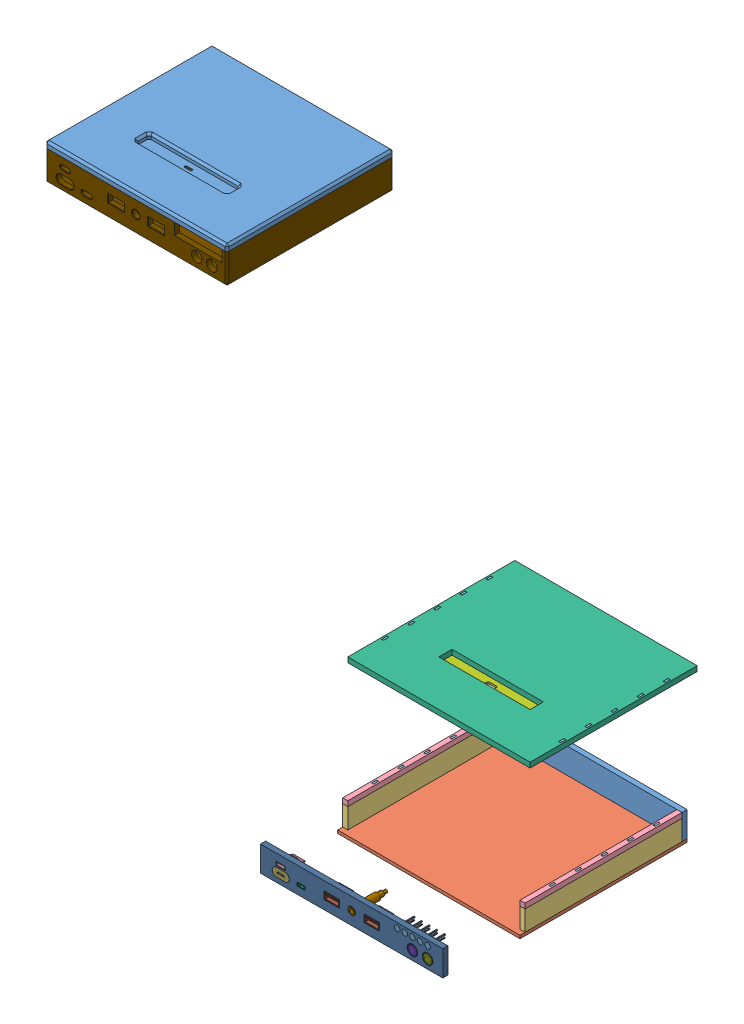
SolidWorks assembly Assem1, configuration Default. Lengths in mm.
Overall size (868.83 145.86 641.02).
69 component instances, 24 part files, 150 mates.
Components (placement in the parent):
- Back rail-1: Back rail [Default] at (72.2044 136.4605 98.1346) size (180 25 5)
- Bottom-1: Bottom [Default] at (72.2044 133.4605 178.1346) size (180 3 165)
- bottom of side rail-1: bottom of side rail [Default] at (-15.2956 156.4605 178.1346) x (0 0 -1) z (-1 0 0) size (155 20 5)
- top of side rail-1: top of side rail [Default] at (-14.7956 156.4605 178.1346) x (0 0 -1) z (1 0 0) size (155 5 5)
- bottom of side rail-2: bottom of side rail [Default] at (159.7044 136.4605 178.1346) x (0 0 -1) z (1 0 0) size (155 20 5)
- top of side rail-2: top of side rail [Default] at (160.2044 156.4605 178.1346) x (0 0 -1) z (1 0 0) size (155 5 5)
- Cell-1: Cell [Default] at (12.7044 136.4705 196.1346) x (-1 0 0) z (0 0 -1) size (51 9.02 83) (hidden)
- Cell-2: Cell [Default] at (131.7044 145.4905 196.1346) x (-1 0 0) z (0 0 -1) size (51 9.02 83) (hidden)
- Cell-3: Cell [Default] at (131.7044 136.4705 196.1346) x (-1 0 0) z (0 0 -1) size (51 9.02 83) (hidden)
- Cell-4: Cell [Default] at (12.7044 145.4905 196.1346) x (-1 0 0) z (0 0 -1) size (51 9.02 83) (hidden)
- Cell-5: Cell [Default] at (115.7044 136.4705 126.1346) x (0 0 1) z (-1 0 0) size (51 9.02 83) (hidden)
- Cell-6: Cell [Default] at (115.7044 145.4905 126.1346) x (0 0 1) z (-1 0 0) size (51 9.02 83) (hidden)
- Cell-7: Cell [Default] at (28.7044 145.4905 126.1346) x (0 0 -1) z (1 0 0) size (51 9.02 83) (hidden)
- Cell-8: Cell [Default] at (28.7044 136.4705 126.1346) x (0 0 -1) z (1 0 0) size (51 9.02 83) (hidden)
- Charger-1: Charger [Default] at (93.2044 141.6605 182.1346) size (20 4.21 35) (hidden)
- Charger-2: Charger [Default] at (93.2044 137.4605 182.1346) size (20 4.21 35) (hidden)
- Charger-3: Charger [Default] at (93.2044 145.8605 182.1346) size (20 4.21 35) (hidden)
- Charger-4: Charger [Default] at (93.2044 150.0605 182.1346) size (20 4.21 35) (hidden)
- Booster-1: Booster [Default] at (49.2044 140.6605 220.1346) size (16 4.2 35) (hidden)
- Booster-2: Booster [Default] at (49.2044 136.4605 220.1346) size (16 4.2 35) (hidden)
- Booster-3: Booster [Default] at (49.2044 136.4605 182.1346) size (16 4.2 35) (hidden)
- Booster-4: Booster [Default] at (49.2044 140.6605 182.1346) size (16 4.2 35) (hidden)
- Booster-5: Booster [Default] at (49.2044 144.8605 182.1346) size (16 4.2 35) (hidden)
- Booster-6: Booster [Default] at (49.2044 144.8605 220.1346) size (16 4.2 35) (hidden)
- Top-1: Top [Default] at (72.2044 161.4605 178.1346) size (180 5 165) (hidden)
- Magnet-1: Magnet [Default] at (158.7044 158.9605 226.3346) x (0 0 -1) z (1 0 0) size (5 5 2)
- Magnet-2: Magnet [Default] at (158.7044 158.9605 200.5846) x (0 0 -1) z (1 0 0) size (5 5 2)
- Magnet-3: Magnet [Default] at (158.7044 158.9605 148.8846) x (0 0 -1) z (1 0 0) size (5 5 2)
- Magnet-4: Magnet [Default] at (-16.2956 158.9605 123.3346) x (0 0 -1) z (1 0 0) size (5 5 2)
- Magnet-5: Magnet [Default] at (158.7044 158.9605 174.6346) x (0 0 -1) z (1 0 0) size (5 5 2)
- Magnet-6: Magnet [Default] at (158.7044 158.9605 123.1346) x (0 0 -1) z (1 0 0) size (5 5 2)
- Magnet-7: Magnet [Default] at (-16.2956 158.9605 148.8846) x (0 0 -1) z (1 0 0) size (5 5 2)
- Magnet-8: Magnet [Default] at (-16.2956 158.9605 174.8346) x (0 0 -1) z (1 0 0) size (5 5 2)
- Magnet-9: Magnet [Default] at (-16.2956 158.9605 200.5846) x (0 0 -1) z (1 0 0) size (5 5 2)
- Magnet-10: Magnet [Default] at (-16.2956 158.9605 226.3346) x (0 0 -1) z (1 0 0) size (5 5 2)
- Top-2: Top [Default] at (72.0511 274.3239 168.0274) size (180 5 165)
- top2-1: top2 [Default] at (72.0511 272.3239 199.5274) size (100 2 30)
- Magnet-11: Magnet [Default] at (-16.4489 276.8239 216.0274) x (0 0 -1) z (1 0 0) size (5 5 2)
- Magnet-12: Magnet [Default] at (-16.4489 276.8239 190.2774) x (0 0 -1) z (1 0 0) size (5 5 2)
- Magnet-13: Magnet [Default] at (-16.4489 276.8239 138.7774) x (0 0 -1) z (1 0 0) size (5 5 2)
- Magnet-14: Magnet [Default] at (-16.4489 276.8239 164.5274) x (0 0 -1) z (1 0 0) size (5 5 2)
- Magnet-15: Magnet [Default] at (-16.4489 276.8239 113.0274) x (0 0 -1) z (1 0 0) size (5 5 2)
- Magnet-16: Magnet [Default] at (158.5511 276.8239 113.2274) x (0 0 -1) z (1 0 0) size (5 5 2)
- Magnet-17: Magnet [Default] at (158.5511 276.8239 190.4774) x (0 0 -1) z (1 0 0) size (5 5 2)
- Magnet-18: Magnet [Default] at (158.5511 276.8239 138.9774) x (0 0 -1) z (1 0 0) size (5 5 2)
- Magnet-19: Magnet [Default] at (158.5511 276.8239 216.2274) x (0 0 -1) z (1 0 0) size (5 5 2)
- Magnet-20: Magnet [Default] at (158.5511 276.8239 164.7274) x (0 0 -1) z (1 0 0) size (5 5 2)
- LPort-1: LPort [Default] at (111.5511 268.3239 175.5274) x (-1 0 0) z (0 0 -1) size (13 6 10)
- Dock-1: Dock [Default] at (72.0511 256.3239 199.5274) size (14 25 10) (hidden)
- FET-1: FET [Default] at (94.7044 143.9605 215.6346) x (0 1 0) z (1 0 0) size (11 9 20) (hidden)
- FET-2: FET [Default] at (94.7044 143.9605 206.6346) x (0 1 0) z (1 0 0) size (11 9 20) (hidden)
- FET-3: FET [Default] at (94.7044 143.9605 224.6346) x (0 1 0) z (1 0 0) size (11 9 20) (hidden)
- FrontIO-1: FrontIO [Default] at (49.7936 127.9248 301.8725) size (180.06 25.43 34.2)
  - aux-jack-1: aux-jack [Default] at (22.4107 22.4035 9.9667) size (7 7 34.2)
  - Front-1: Front [Default] at (22.4107 22.4035 29.9667) x (0.999997 0.002406 0) z (0.002406 -0.999997 0) size (180 5 25)
  - USB-Port-1: USB-Port [Default] at (42.1606 22.451 19.9667) x (0.999997 0.002406 0) z (0 0 1) size (15 7 15)
  - USB-Port-2: USB-Port [Default] at (2.6608 22.356 19.9667) x (0.999997 0.002406 0) z (0 0 1) size (15 7 15)
  - Lightning-c-1: Lightning-c [Default] at (-51.7901 21.1486 19.9667) x (0.999997 0.002406 0) z (0 0 1) size (17 8.5 15)
  - usb-c-port-1: usb-c-port [Default] at (-47.5981 25.9851 21.9667) x (0.999997 0.002406 0) z (0 0 1) size (12 4.5 18)
  - LeD-1: LeD [Default] at (97.3924 30.0839 28.9667) size (6.5 6.5 17)
  - LeD-2: LeD [Default] at (89.8925 30.0659 28.9667) size (6.5 6.5 17)
  - LeD-3: LeD [Default] at (82.3501 30.0477 28.9667) size (6.5 6.5 17)
  - LeD-4: LeD [Default] at (74.8501 30.0297 28.9667) size (6.5 6.5 17)
  - LeD-5: LeD [Default] at (67.3501 30.0116 28.9667) size (6.5 6.5 17)
  - USB-b-1: USB-b [Default] at (-27.5801 18.5332 28.9667) x (0.999997 0.002406 0) z (0 0 1) size (11 4 9)
  - PWR-1: PWR [Default] at (97.4195 18.8339 31.9667) size (9 9 9.01)
  - CHG-1: CHG [Default] at (82.4195 18.7979 31.9667) size (9 9 9.01)
- corian-max-1: corian-max [Default] at (-616.5978 146.087 -221.484) x (0 0 -1) z (1 0 0) size (165 30 180)
- max-corian-2-1: max-corian-2 [Default] at (-616.5978 176.087 -221.484) size (180 6 165)
Mates (geometry in assembly coordinates):
- Coincident3: coincident: plane of Back rail-1 through (72.2044 136.4605 98.1346) normal (0 -1 0); plane of Bottom-1 through (72.2044 136.4605 178.1346) normal (0 1 0)
- Coincident4: coincident: plane of Back rail-1 through (-17.7956 161.4605 95.6346) normal (0 0 -1); plane of Bottom-1 through (-17.7956 136.4605 95.6346) normal (0 0 -1)
- Coincident5: coincident: plane of bottom of side rail-1 through (-15.2956 156.4605 178.1346) normal (0 1 0); plane of top of side rail-1 through (-14.7956 156.4605 178.1346) normal (0 -1 0)
- Coincident6: coincident: plane of bottom of side rail-1 through (-12.7956 136.4605 100.6346) normal (0 0 -1); plane of top of side rail-1 through (-17.7956 161.4605 100.6346) normal (0 0 -1)
- Coincident7: coincident: plane of bottom of side rail-1 through (-17.7956 136.4605 255.6346) normal (-1 0 0); plane of top of side rail-1 through (-17.7956 161.4605 255.6346) normal (-1 0 0)
- Coincident9: coincident: plane of Bottom-1 through (72.2044 136.4605 178.1346) normal (0 1 0); plane of bottom of side rail-1 through (-15.2956 136.4605 178.1346) normal (0 -1 0)
- Coincident11: coincident: plane of Bottom-1 through (-17.7956 136.4605 95.6346) normal (-1 0 0); plane of bottom of side rail-1 through (-17.7956 136.4605 255.6346) normal (-1 0 0)
- Coincident13: coincident: plane of bottom of side rail-2 through (159.7044 156.4605 178.1346) normal (0 1 0); plane of top of side rail-2 through (160.2044 156.4605 178.1346) normal (0 -1 0)
- Coincident14: coincident: plane of bottom of side rail-2 through (157.2044 156.4605 255.6346) normal (0 0 1); plane of top of side rail-2 through (157.2044 161.4605 255.6346) normal (0 0 1)
- Coincident15: coincident: plane of bottom of side rail-2 through (157.2044 156.4605 255.6346) normal (-1 0 0); plane of top of side rail-2 through (157.2044 161.4605 255.6346) normal (-1 0 0)
- Coincident16: coincident: plane of Bottom-1 through (72.2044 136.4605 178.1346) normal (0 1 0); plane of bottom of side rail-2 through (159.7044 136.4605 178.1346) normal (0 -1 0)
- Coincident17: coincident: plane of Bottom-1 through (162.2044 136.4605 95.6346) normal (1 0 0); plane of bottom of side rail-2 through (162.2044 156.4605 255.6346) normal (1 0 0)
- Coincident18: coincident: plane of Back rail-1 through (-17.7956 161.4605 100.6346) normal (0 0 1); plane of bottom of side rail-2 through (157.2044 156.4605 100.6346) normal (0 0 -1)
- Coincident19: coincident: plane of Bottom-1 through (-17.7956 136.4605 95.6346) normal (-1 0 0); plane of Back rail-1 through (-17.7956 161.4605 95.6346) normal (-1 0 0)
- Coincident20: coincident: plane of Back rail-1 through (-17.7956 161.4605 100.6346) normal (0 0 1); plane of bottom of side rail-1 through (-12.7956 136.4605 100.6346) normal (0 0 -1)
- Coincident21: coincident: plane of Cell-1 through (12.7044 145.4805 196.1346) normal (0 1 0); plane of Cell-4 through (12.7044 145.4805 196.1346) normal (0 -1 0)
- Coincident22: coincident: plane of Cell-1 through (38.2044 145.4705 237.6346) normal (1 0 0); plane of Cell-4 through (38.2044 154.4905 237.6346) normal (1 0 0)
- Coincident23: coincident: plane of Cell-1 through (38.2044 145.4705 237.6346) normal (0 0 1); plane of Cell-4 through (38.2044 154.4905 237.6346) normal (0 0 1)
- Coincident24: coincident: plane of Cell-2 through (131.7044 145.4805 196.1346) normal (0 -1 0); plane of Cell-3 through (131.7044 145.4805 196.1346) normal (0 1 0)
- Coincident25: coincident: plane of Cell-2 through (157.2044 154.4905 237.6346) normal (1 0 0); plane of Cell-3 through (157.2044 145.4705 237.6346) normal (1 0 0)
- Coincident26: coincident: plane of Cell-2 through (157.2044 154.4905 237.6346) normal (0 0 1); plane of Cell-3 through (157.2044 145.4705 237.6346) normal (0 0 1)
- Coincident27: coincident: plane of Bottom-1 through (72.2044 136.4605 178.1346) normal (0 1 0); plane of Cell-3 through (131.7044 136.4605 196.1346) normal (0 -1 0)
- Coincident28: coincident: plane of bottom of side rail-2 through (157.2044 156.4605 255.6346) normal (-1 0 0); plane of Cell-3 through (157.2044 145.4705 237.6346) normal (1 0 0)
- Coincident29: coincident: plane of Bottom-1 through (72.2044 136.4605 178.1346) normal (0 1 0); plane of Cell-1 through (12.7044 136.4605 196.1346) normal (0 -1 0)
- Coincident30: coincident: plane of bottom of side rail-1 through (-12.7956 136.4605 255.6346) normal (1 0 0); plane of Cell-4 through (-12.7956 154.4905 237.6346) normal (-1 0 0)
- Coincident31: coincident: plane of Cell-5 through (115.7044 145.4805 126.1346) normal (0 1 0); plane of Cell-6 through (115.7044 145.4805 126.1346) normal (0 -1 0)
- Coincident32: coincident: plane of Cell-5 through (157.2044 145.4705 100.6346) normal (0 0 -1); plane of Cell-6 through (157.2044 154.4905 100.6346) normal (0 0 -1)
- Coincident33: coincident: plane of Cell-5 through (157.2044 145.4705 100.6346) normal (1 0 0); plane of Cell-6 through (157.2044 154.4905 100.6346) normal (1 0 0)
- Coincident35: coincident: plane of Bottom-1 through (72.2044 136.4605 178.1346) normal (0 1 0); plane of Cell-5 through (115.7044 136.4605 126.1346) normal (0 -1 0)
- Coincident36: coincident: plane of Back rail-1 through (-17.7956 161.4605 100.6346) normal (0 0 1); plane of Cell-6 through (157.2044 154.4905 100.6346) normal (0 0 -1)
- Coincident37: coincident: plane of bottom of side rail-2 through (157.2044 156.4605 255.6346) normal (-1 0 0); plane of Cell-6 through (157.2044 154.4905 100.6346) normal (1 0 0)
- Distance1: distance = 3 mm: plane of Cell-2 through (157.2044 154.4905 154.6346) normal (0 0 -1); plane of Cell-6 through (157.2044 154.4905 151.6346) normal (0 0 1)
- Coincident39: coincident: plane of Cell-7 through (-12.7956 154.4905 151.6346) normal (0 0 1); plane of Cell-8 through (-12.7956 145.4705 151.6346) normal (0 0 1)
- Coincident40: coincident: plane of Cell-7 through (28.7044 145.4805 126.1346) normal (0 -1 0); plane of Cell-8 through (28.7044 145.4805 126.1346) normal (0 1 0)
- Coincident41: coincident: plane of Cell-7 through (-12.7956 154.4905 151.6346) normal (-1 0 0); plane of Cell-8 through (-12.7956 145.4705 151.6346) normal (-1 0 0)
- Coincident42: coincident: plane of Bottom-1 through (72.2044 136.4605 178.1346) normal (0 1 0); plane of Cell-8 through (28.7044 136.4605 126.1346) normal (0 -1 0)
- Coincident43: coincident: plane of Back rail-1 through (-17.7956 161.4605 100.6346) normal (0 0 1); plane of Cell-7 through (-12.7956 154.4905 100.6346) normal (0 0 -1)
- Coincident44: coincident: plane of bottom of side rail-1 through (-12.7956 136.4605 255.6346) normal (1 0 0); plane of Cell-7 through (-12.7956 154.4905 151.6346) normal (-1 0 0)
- Distance2: distance = 3 mm: plane of Cell-4 through (38.2044 154.4905 154.6346) normal (0 0 -1); plane of Cell-7 through (-12.7956 154.4905 151.6346) normal (0 0 1)
- Coincident45: coincident: plane of Charger-1 through (93.2044 141.6605 182.1346) normal (0 -1 0); plane of Charger-2 through (93.2044 141.6605 182.1346) normal (0 1 0)
- Coincident46: coincident: plane of Charger-1 through (93.2044 145.8605 182.1346) normal (0 1 0); plane of Charger-3 through (93.2044 145.8605 182.1346) normal (0 -1 0)
- Coincident47: coincident: plane of Charger-3 through (93.2044 150.0605 182.1346) normal (0 1 0); plane of Charger-4 through (93.2044 150.0605 182.1346) normal (0 -1 0)
- Coincident48: coincident: plane of Charger-2 through (103.2044 138.6605 164.6346) normal (1 0 0); plane of Charger-1 through (103.2044 142.8605 164.6346) normal (1 0 0)
- Coincident49: coincident: plane of Charger-1 through (103.2044 142.8605 164.6346) normal (1 0 0); plane of Charger-3 through (103.2044 147.0605 164.6346) normal (1 0 0)
- Coincident50: coincident: plane of Charger-3 through (103.2044 147.0605 164.6346) normal (1 0 0); plane of Charger-4 through (103.2044 151.2605 164.6346) normal (1 0 0)
- Coincident51: coincident: plane of Charger-1 through (83.2044 142.8605 199.6346) normal (0 0 1); plane of Charger-2 through (83.2044 138.6605 199.6346) normal (0 0 1)
- Coincident52: coincident: plane of Charger-1 through (83.2044 142.8605 199.6346) normal (0 0 1); plane of Charger-3 through (83.2044 147.0605 199.6346) normal (0 0 1)
- Coincident53: coincident: plane of Charger-3 through (83.2044 147.0605 199.6346) normal (0 0 1); plane of Charger-4 through (83.2044 151.2605 199.6346) normal (0 0 1)
- Distance3: distance = 1 mm: plane of Charger-2 through (93.2044 137.4605 182.1346) normal (0 -1 0); plane of Bottom-1 through (72.2044 136.4605 178.1346) normal (0 1 0)
- Distance4: distance = 3 mm: plane of Charger-4 through (103.2044 151.2605 164.6346) normal (1 0 0); plane of Cell-2 through (106.2044 154.4905 237.6346) normal (-1 0 0)
- Distance5: distance = 13 mm: plane of Cell-6 through (157.2044 154.4905 151.6346) normal (0 0 1); plane of Charger-4 through (83.2044 151.2605 164.6346) normal (0 0 -1)
- Coincident59: coincident: plane of Booster-1 through (41.2044 141.8605 237.6346) normal (0 0 1); plane of Booster-2 through (41.2044 137.6605 237.6346) normal (0 0 1)
- Coincident60: coincident: plane of Booster-1 through (41.2044 141.8605 237.6346) normal (0 0 1); plane of Booster-6 through (41.2044 146.0605 237.6346) normal (0 0 1)
- Coincident61: coincident: plane of Booster-1 through (41.2044 141.8605 202.6346) normal (-1 0 0); plane of Booster-2 through (41.2044 137.6605 202.6346) normal (-1 0 0)
- Coincident62: coincident: plane of Booster-1 through (41.2044 141.8605 202.6346) normal (-1 0 0); plane of Booster-6 through (41.2044 146.0605 202.6346) normal (-1 0 0)
- Coincident65: coincident: plane of Booster-1 through (49.2044 144.8605 220.1346) normal (0 1 0); plane of Booster-6 through (49.2044 144.8605 220.1346) normal (0 -1 0)
- Coincident66: coincident: plane of Booster-1 through (49.2044 140.6605 220.1346) normal (0 -1 0); plane of Booster-2 through (49.2044 140.6605 220.1346) normal (0 1 0)
- Coincident67: coincident: plane of Booster-3 through (49.2044 140.6605 182.1346) normal (0 1 0); plane of Booster-4 through (49.2044 140.6605 182.1346) normal (0 -1 0)
- Coincident68: coincident: plane of Booster-4 through (49.2044 144.8605 182.1346) normal (0 1 0); plane of Booster-5 through (49.2044 144.8605 182.1346) normal (0 -1 0)
- Coincident69: coincident: plane of Booster-3 through (57.2044 137.6605 164.6346) normal (1 0 0); plane of Booster-4 through (57.2044 141.8605 164.6346) normal (1 0 0)
- Coincident70: coincident: plane of Booster-4 through (57.2044 141.8605 164.6346) normal (1 0 0); plane of Booster-5 through (57.2044 146.0605 164.6346) normal (1 0 0)
- Coincident72: coincident: plane of Booster-3 through (41.2044 137.6605 199.6346) normal (0 0 1); plane of Booster-4 through (41.2044 141.8605 199.6346) normal (0 0 1)
- Coincident73: coincident: plane of Booster-5 through (41.2044 146.0605 199.6346) normal (0 0 1); plane of Booster-4 through (41.2044 141.8605 199.6346) normal (0 0 1)
- Distance7: distance = 3 mm: plane of Booster-6 through (41.2044 146.0605 202.6346) normal (0 0 -1); plane of Booster-5 through (41.2044 146.0605 199.6346) normal (0 0 1)
- Coincident77: coincident: plane of Booster-5 through (57.2044 146.0605 164.6346) normal (1 0 0); plane of Booster-6 through (57.2044 146.0605 202.6346) normal (1 0 0)
- Coincident78: coincident: plane of Booster-5 through (49.2044 146.0605 182.1346) normal (0 1 0); plane of Booster-6 through (49.2044 146.0605 220.1346) normal (0 1 0)
- Coincident79: coincident: plane of Bottom-1 through (72.2044 136.4605 178.1346) normal (0 1 0); plane of Booster-2 through (49.2044 136.4605 220.1346) normal (0 -1 0)
- Coincident80: coincident: plane of Charger-4 through (83.2044 151.2605 164.6346) normal (0 0 -1); plane of Booster-5 through (41.2044 146.0605 164.6346) normal (0 0 -1)
- Distance8: distance = 3 mm: plane of Cell-1 through (38.2044 145.4705 237.6346) normal (1 0 0); plane of Booster-6 through (41.2044 146.0605 202.6346) normal (-1 0 0)
- Coincident81: coincident: plane of top of side rail-2 through (160.7044 161.4605 223.6346) normal (-1 0 0); plane of Magnet-1 through (160.7044 158.9605 226.3346) normal (1 0 0)
- Coincident82: coincident: plane of top of side rail-2 through (158.7044 161.4605 228.8346) normal (0 0 -1); plane of Magnet-1 through (160.7044 161.4605 228.8346) normal (0 0 1)
- Coincident83: coincident: plane of top of side rail-2 through (160.2044 161.4605 178.1346) normal (0 1 0); plane of Magnet-1 through (160.7044 161.4605 228.8346) normal (0 1 0)
- Coincident84: coincident: plane of top of side rail-2 through (158.7044 161.4605 203.0846) normal (0 0 -1); plane of Magnet-2 through (160.7044 161.4605 203.0846) normal (0 0 1)
- Coincident86: coincident: plane of top of side rail-2 through (160.7044 161.4605 197.8846) normal (-1 0 0); plane of Magnet-2 through (160.7044 158.9605 200.5846) normal (1 0 0)
- Coincident90: coincident: plane of top of side rail-2 through (160.2044 161.4605 178.1346) normal (0 1 0); plane of Magnet-2 through (160.7044 161.4605 203.0846) normal (0 1 0)
- Coincident91: coincident: plane of top of side rail-2 through (160.2044 161.4605 178.1346) normal (0 1 0); plane of Magnet-5 through (160.7044 161.4605 177.1346) normal (0 1 0)
- Coincident92: coincident: plane of top of side rail-2 through (158.7044 161.4605 172.1346) normal (0 0 1); plane of Magnet-5 through (160.7044 161.4605 172.1346) normal (0 0 -1)
- Coincident94: coincident: plane of top of side rail-2 through (160.7044 161.4605 172.1346) normal (-1 0 0); plane of Magnet-5 through (160.7044 158.9605 174.6346) normal (1 0 0)
- Coincident95: coincident: plane of top of side rail-2 through (158.7044 161.4605 146.3846) normal (0 0 1); plane of Magnet-3 through (160.7044 161.4605 146.3846) normal (0 0 -1)
- Coincident96: coincident: plane of top of side rail-2 through (160.7044 161.4605 146.3846) normal (-1 0 0); plane of Magnet-3 through (160.7044 158.9605 148.8846) normal (1 0 0)
- Coincident97: coincident: plane of top of side rail-2 through (160.2044 161.4605 178.1346) normal (0 1 0); plane of Magnet-3 through (160.7044 161.4605 151.3846) normal (0 1 0)
- Coincident98: coincident: plane of top of side rail-2 through (158.7044 161.4605 120.6346) normal (0 0 1); plane of Magnet-6 through (160.7044 161.4605 120.6346) normal (0 0 -1)
- Coincident99: coincident: plane of top of side rail-2 through (160.7044 161.4605 120.6346) normal (-1 0 0); plane of Magnet-6 through (160.7044 158.9605 123.1346) normal (1 0 0)
- Coincident100: coincident: plane of top of side rail-2 through (160.2044 161.4605 178.1346) normal (0 1 0); plane of Magnet-6 through (160.7044 161.4605 125.6346) normal (0 1 0)
- Coincident101: coincident: plane of top of side rail-1 through (-14.2956 161.4605 120.6346) normal (-1 0 0); plane of Magnet-4 through (-14.2956 158.9605 123.3346) normal (1 0 0)
- Coincident102: coincident: plane of top of side rail-1 through (-16.2956 161.4605 125.8346) normal (0 0 -1); plane of Magnet-4 through (-14.2956 161.4605 125.8346) normal (0 0 1)
- Coincident104: coincident: plane of top of side rail-1 through (-14.7956 161.4605 178.1346) normal (0 1 0); plane of Magnet-4 through (-14.2956 161.4605 125.8346) normal (0 1 0)
- Coincident105: coincident: plane of Magnet-7 through (-16.2956 158.9605 148.8846) normal (-1 0 0); plane of Magnet-8 through (-16.2956 158.9605 174.8346) normal (-1 0 0)
- Coincident106: coincident: plane of Magnet-8 through (-16.2956 158.9605 174.8346) normal (-1 0 0); plane of Magnet-9 through (-16.2956 158.9605 200.5846) normal (-1 0 0)
- Coincident107: coincident: plane of Magnet-9 through (-16.2956 158.9605 200.5846) normal (-1 0 0); plane of Magnet-10 through (-16.2956 158.9605 226.3346) normal (-1 0 0)
- Coincident108: coincident: plane of top of side rail-1 through (-16.2956 161.4605 146.3846) normal (1 0 0); plane of Magnet-7 through (-16.2956 158.9605 148.8846) normal (-1 0 0)
- Coincident109: coincident: plane of top of side rail-1 through (-16.2956 161.4605 146.3846) normal (0 0 1); plane of Magnet-7 through (-14.2956 161.4605 146.3846) normal (0 0 -1)
- Coincident110: coincident: plane of Magnet-7 through (-14.2956 161.4605 151.3846) normal (0 1 0); plane of Magnet-8 through (-14.2956 161.4605 177.3346) normal (0 1 0)
- Coincident111: coincident: plane of Magnet-8 through (-14.2956 161.4605 177.3346) normal (0 1 0); plane of Magnet-9 through (-14.2956 161.4605 203.0846) normal (0 1 0)
- Coincident112: coincident: plane of Magnet-9 through (-14.2956 161.4605 203.0846) normal (0 1 0); plane of Magnet-10 through (-14.2956 161.4605 228.8346) normal (0 1 0)
- Coincident113: coincident: plane of top of side rail-1 through (-16.2956 161.4605 228.8346) normal (0 0 -1); plane of Magnet-10 through (-14.2956 161.4605 228.8346) normal (0 0 1)
- Coincident114: coincident: plane of top of side rail-1 through (-16.2956 161.4605 203.0846) normal (0 0 -1); plane of Magnet-9 through (-14.2956 161.4605 203.0846) normal (0 0 1)
- Coincident115: coincident: plane of top of side rail-1 through (-16.2956 161.4605 177.3346) normal (0 0 -1); plane of Magnet-8 through (-14.2956 161.4605 177.3346) normal (0 0 1)
- Coincident116: coincident: plane of top of side rail-1 through (-14.7956 161.4605 178.1346) normal (0 1 0); plane of Magnet-7 through (-14.2956 161.4605 151.3846) normal (0 1 0)
- Coincident117: coincident: plane of Top-2 through (72.0511 274.3239 168.0274) normal (0 -1 0); plane of top2-1 through (72.0511 274.3239 199.5274) normal (0 1 0)
- Distance9: distance = 36 mm: plane of top2-1 through (22.0511 274.3239 214.5274) normal (0 0 1); plane of Top-2 through (-17.9489 279.3239 250.5274) normal (0 0 1)
- Distance10: distance = 40 mm: plane of top2-1 through (122.0511 274.3239 184.5274) normal (1 0 0); plane of Top-2 through (162.0511 279.3239 85.5274) normal (1 0 0)
- Coincident120: coincident: plane of Magnet-16 through (160.5511 279.3239 115.7274) normal (0 1 0); plane of Magnet-17 through (160.5511 279.3239 192.9774) normal (0 1 0)
- Coincident121: coincident: plane of Magnet-17 through (160.5511 279.3239 192.9774) normal (0 1 0); plane of Magnet-18 through (160.5511 279.3239 141.4774) normal (0 1 0)
- Coincident122: coincident: plane of Magnet-18 through (160.5511 279.3239 141.4774) normal (0 1 0); plane of Magnet-19 through (160.5511 279.3239 218.7274) normal (0 1 0)
- Coincident123: coincident: plane of Magnet-16 through (160.5511 279.3239 115.7274) normal (0 1 0); plane of Magnet-20 through (160.5511 279.3239 167.2274) normal (0 1 0)
- Coincident124: coincident: plane of Magnet-16 through (160.5511 276.8239 113.2274) normal (1 0 0); plane of Magnet-20 through (160.5511 276.8239 164.7274) normal (1 0 0)
- Coincident125: coincident: plane of Magnet-17 through (160.5511 276.8239 190.4774) normal (1 0 0); plane of Magnet-20 through (160.5511 276.8239 164.7274) normal (1 0 0)
- Coincident126: coincident: plane of Magnet-17 through (160.5511 276.8239 190.4774) normal (1 0 0); plane of Magnet-19 through (160.5511 276.8239 216.2274) normal (1 0 0)
- Coincident127: coincident: plane of Magnet-16 through (160.5511 276.8239 113.2274) normal (1 0 0); plane of Magnet-18 through (160.5511 276.8239 138.9774) normal (1 0 0)
- Coincident128: coincident: plane of Top-2 through (160.5511 279.3239 218.7274) normal (0 0 -1); plane of Magnet-19 through (160.5511 279.3239 218.7274) normal (0 0 1)
- Coincident129: coincident: plane of Top-2 through (160.5511 279.3239 192.9774) normal (0 0 -1); plane of Magnet-17 through (160.5511 279.3239 192.9774) normal (0 0 1)
- Coincident130: coincident: plane of Top-2 through (160.5511 279.3239 167.2274) normal (0 0 -1); plane of Magnet-20 through (160.5511 279.3239 167.2274) normal (0 0 1)
- Coincident131: coincident: plane of Top-2 through (160.5511 279.3239 141.4774) normal (0 0 -1); plane of Magnet-18 through (160.5511 279.3239 141.4774) normal (0 0 1)
- Coincident132: coincident: plane of Top-2 through (160.5511 279.3239 115.7274) normal (0 0 -1); plane of Magnet-16 through (160.5511 279.3239 115.7274) normal (0 0 1)
- Coincident133: coincident: plane of Top-2 through (160.5511 279.3239 110.5274) normal (-1 0 0); plane of Magnet-16 through (160.5511 276.8239 113.2274) normal (1 0 0)
- Coincident135: coincident: plane of Top-2 through (72.0511 274.3239 168.0274) normal (0 -1 0); plane of Magnet-16 through (160.5511 274.3239 115.7274) normal (0 -1 0)
- Coincident136: coincident: plane of Magnet-14 through (-16.4489 276.8239 164.5274) normal (-1 0 0); plane of Magnet-15 through (-16.4489 276.8239 113.0274) normal (-1 0 0)
- Coincident137: coincident: plane of Magnet-13 through (-16.4489 276.8239 138.7774) normal (-1 0 0); plane of Magnet-14 through (-16.4489 276.8239 164.5274) normal (-1 0 0)
- Coincident138: coincident: plane of Magnet-12 through (-16.4489 276.8239 190.2774) normal (-1 0 0); plane of Magnet-13 through (-16.4489 276.8239 138.7774) normal (-1 0 0)
- Coincident139: coincident: plane of Magnet-11 through (-16.4489 276.8239 216.0274) normal (-1 0 0); plane of Magnet-15 through (-16.4489 276.8239 113.0274) normal (-1 0 0)
- Coincident140: coincident: plane of Magnet-11 through (-14.4489 279.3239 218.5274) normal (0 1 0); plane of Magnet-15 through (-14.4489 279.3239 115.5274) normal (0 1 0)
- Coincident141: coincident: plane of Magnet-14 through (-14.4489 279.3239 167.0274) normal (0 1 0); plane of Magnet-15 through (-14.4489 279.3239 115.5274) normal (0 1 0)
- Coincident142: coincident: plane of Magnet-13 through (-14.4489 279.3239 141.2774) normal (0 1 0); plane of Magnet-15 through (-14.4489 279.3239 115.5274) normal (0 1 0)
- Coincident143: coincident: plane of Magnet-12 through (-14.4489 279.3239 192.7774) normal (0 1 0); plane of Magnet-15 through (-14.4489 279.3239 115.5274) normal (0 1 0)
- Coincident144: coincident: plane of Top-2 through (-16.4489 279.3239 110.5274) normal (0 0 1); plane of Magnet-15 through (-14.4489 279.3239 110.5274) normal (0 0 -1)
- Coincident145: coincident: plane of Top-2 through (-16.4489 279.3239 136.2774) normal (0 0 1); plane of Magnet-13 through (-14.4489 279.3239 136.2774) normal (0 0 -1)
- Coincident146: coincident: plane of Top-2 through (-16.4489 279.3239 162.0274) normal (0 0 1); plane of Magnet-14 through (-14.4489 279.3239 162.0274) normal (0 0 -1)
- Coincident147: coincident: plane of Top-2 through (-16.4489 279.3239 187.7774) normal (0 0 1); plane of Magnet-12 through (-14.4489 279.3239 187.7774) normal (0 0 -1)
- Coincident148: coincident: plane of Top-2 through (-16.4489 279.3239 213.5274) normal (0 0 1); plane of Magnet-11 through (-14.4489 279.3239 213.5274) normal (0 0 -1)
- Coincident149: coincident: plane of Top-2 through (-16.4489 279.3239 213.5274) normal (1 0 0); plane of Magnet-11 through (-16.4489 276.8239 216.0274) normal (-1 0 0)
- Coincident150: coincident: plane of Top-2 through (72.0511 279.3239 168.0274) normal (0 1 0); plane of Magnet-11 through (-14.4489 279.3239 218.5274) normal (0 1 0)
- Coincident151: coincident: plane of Top-2 through (72.0511 274.3239 168.0274) normal (0 -1 0); plane of LPort-1 through (111.5511 274.3239 175.5274) normal (0 1 0)
- Distance11: distance = 4 mm: plane of LPort-1 through (118.0511 274.3239 180.5274) normal (0 0 1); plane of top2-1 through (22.0511 274.3239 184.5274) normal (0 0 -1)
- Distance12: distance = 4 mm: plane of top2-1 through (122.0511 274.3239 184.5274) normal (1 0 0); plane of LPort-1 through (118.0511 274.3239 180.5274) normal (1 0 0)
- Coincident154: coincident: plane of top2-1 through (72.0511 274.3239 199.5274) normal (0 1 0); plane of Dock-1 through (74.8511 274.3239 199.8274) normal (0 1 0)
- Coincident155: coincident: plane of top2-1 through (69.0511 274.3239 197.0274) normal (0 0 1); plane of Dock-1 through (69.2511 274.3239 197.0274) normal (0 0 -1)
- Coincident157: coincident: line of top2-1 through (77.0511 272.3239 200.0274) axis (0 0 -1); plane of Dock-1 through (77.0511 274.3239 199.8274) normal (1 0 0)
- Coincident158: coincident: plane of FET-1 through (94.7044 143.9605 215.6346) normal (0 0 -1); plane of FET-2 through (94.7044 143.9605 215.6346) normal (0 0 1)
- Coincident159: coincident: plane of FET-1 through (94.7044 143.9605 224.6346) normal (0 0 1); plane of FET-3 through (94.7044 143.9605 224.6346) normal (0 0 -1)
- Coincident160: coincident: plane of FET-1 through (94.7044 149.4605 219.6346) normal (0 1 0); plane of FET-2 through (94.7044 149.4605 210.6346) normal (0 1 0)
- Coincident161: coincident: plane of FET-1 through (94.7044 149.4605 219.6346) normal (0 1 0); plane of FET-3 through (94.7044 149.4605 228.6346) normal (0 1 0)
- Coincident162: coincident: plane of FET-1 through (84.2044 143.9605 219.6346) normal (-1 0 0); plane of FET-2 through (84.2044 143.9605 210.6346) normal (-1 0 0)
- Coincident163: coincident: plane of FET-1 through (84.2044 143.9605 219.6346) normal (-1 0 0); plane of FET-3 through (84.2044 143.9605 228.6346) normal (-1 0 0)
- Distance13: distance = 2 mm: plane of FET-3 through (94.7044 138.4605 228.6346) normal (0 -1 0); plane of Bottom-1 through (72.2044 136.4605 178.1346) normal (0 1 0)
- Distance14: distance = 7 mm: plane of FET-2 through (94.7044 143.9605 206.6346) normal (0 0 -1); plane of Charger-3 through (83.2044 147.0605 199.6346) normal (0 0 1)
- Distance15: distance = 7 mm: plane of FET-1 through (99.2044 143.9605 219.6346) normal (1 0 0); plane of Cell-3 through (106.2044 145.4705 237.6346) normal (-1 0 0)
- Coincident164: coincident: plane of corian-max-1 through (-616.5978 176.087 -221.484) normal (0 1 0); plane of max-corian-2-1 through (-616.5978 176.087 -221.484) normal (0 -1 0)
- Coincident165: coincident: plane of corian-max-1 through (-706.5978 176.087 -138.984) normal (0 0 1); plane of max-corian-2-1 through (-706.5978 182.087 -138.984) normal (0 0 1)
- Coincident166: coincident: plane of corian-max-1 through (-706.5978 176.087 -138.984) normal (-1 0 0); plane of max-corian-2-1 through (-706.5978 182.087 -303.984) normal (-1 0 0)
